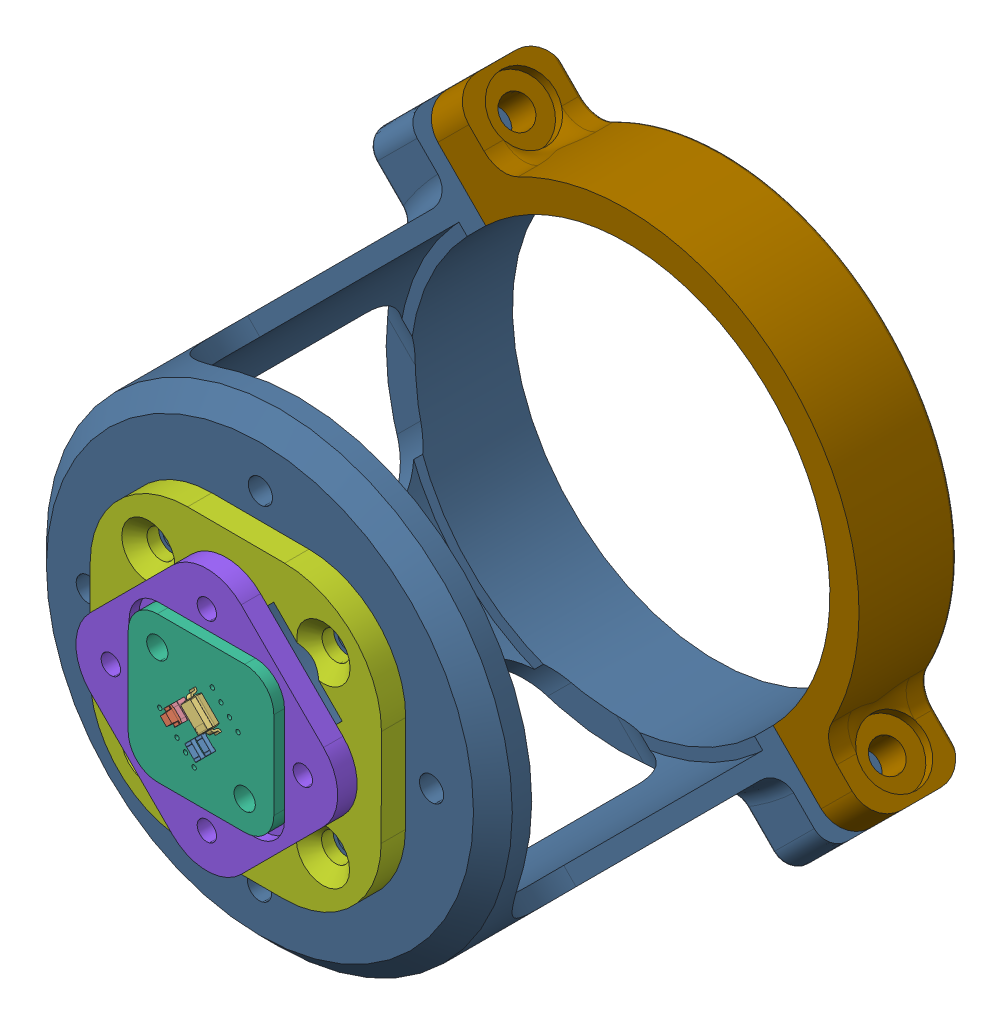
SolidWorks assembly NEW_AS5047_mount_ASS, configuration Default. Lengths in mm.
Overall size (78.46 78.52 54.41).
18 component instances, 10 part files, 13 mates.
Components (placement in the parent):
- as5047-mounting_v2.0.step-1: as5047-mounting_v2.0.step [Default] at (-37.8723 -4.0451 22.4905) size (15 15 3.95)
  - R_0603_1608Metric.step-1: R_0603_1608Metric.step [Default] at (4.1664 -6.9571 1.65) x (-0.707107 0.707107 0) z (0 0 1) size (1.6 0.8 0.45)
    - R_0603_1608Metric-0.step-1: R_0603_1608Metric-0.step [Default] at origin size (1.6 0.8 0.45)
  - LED_0603_1608Metric.step-1: LED_0603_1608Metric.step [Default] at (2.0554 -4.8494 1.65) x (0.707107 -0.707107 0) z (0 0 1) size (1.6 0.8 1.1)
    - LED_0603_1608Metric-1.step-1: LED_0603_1608Metric-1.step [Default] at origin size (1.6 0.8 1.1)
  - D_SOD-123.step-1: D_SOD-123.step [Default] at (5.1024 -3.0451 1.65) x (-0.707107 0.707107 0) z (0 0 1) size (3.8 1.6 1.25)
    - D_SOD_123.step-1: D_SOD_123.step [Default] at origin size (3.8 1.6 1.25)
  - C_0603_1608Metric.step-1: C_0603_1608Metric.step [Default] at (3.1284 -3.7888 1.65) x (-0.707107 0.707107 0) z (0 0 1) size (1.6 0.8 0.8)
    - C_0603_1608Metric-2.step-1: C_0603_1608Metric-2.step [Default] at origin size (1.6 0.8 0.8)
  - R_0603_1608Metric.step-2: R_0603_1608Metric.step [Default] at (5.2316 -5.892 1.65) x (-0.707107 0.707107 0) z (0 0 1) size (1.6 0.8 0.45)
    - R_0603_1608Metric-0.step-1: R_0603_1608Metric-0.step [Default] at origin size (1.6 0.8 0.45)
  - TSSOP-14_4.4x5mm_P0.65mm.step-1: TSSOP-14_4.4x5mm_P0.65mm.step [Default] at (4.5042 -4.549 -0.05) x (0.707107 -0.707107 0) z (0 0 -1) size (6.4 5 1)
    - TSSOP_14_44x5mm_P065mm.step-1: TSSOP_14_44x5mm_P065mm.step [Default] at origin size (6.4 5 1)
  - as5047-mounting_v2.0_PCB.step-1: as5047-mounting_v2.0_PCB.step [Default] at origin size (15 15 1.6)
- SENSOR_SUPP_PL^ROBO_MOTOR_M3508-1: SENSOR_SUPP_PL^ROBO_MOTOR_M3508 [Default] at (-33.4013 -8.5561 17.9905) x (0.999996 -0.002924 0) z (0 0 1) size (30 30 3.5)
- NEW_AS5047_mount-1: NEW_AS5047_mount [Default] at (-33.3723 -8.5451 23.4905) x (0.707107 -0.707107 0) z (0.707107 0.707107 0) size (22 2 22)
- CLAMP_HALF^ROBO_MOTOR_M3508-1: CLAMP_HALF^ROBO_MOTOR_M3508 [Default] at (-32.6921 -7.851 -56.5095) x (0.709172 0.705036 0) z (0.705036 -0.709172 0) size (23.5 10 62)
- SW_SENSOR_CL_RING^ROBO_MOTOR_M3508-1: SW_SENSOR_CL_RING^ROBO_MOTOR_M3508 [Default] at (-33.4013 -8.5561 -23.0095) x (0.709172 0.705036 0) z (0.705036 -0.709172 0) size (48 47.01 62)
Mates (geometry in assembly coordinates):
- Coincident3: coincident anti-aligned: plane of as5047-mounting_v2.0.step-1/as5047-mounting_v2.0_PCB.step-1 through (-33.3723 -8.5451 22.4905) normal (0 0 -1); plane of NEW_AS5047_mount-1 through (-33.3723 -8.5451 22.4905) normal (0 0 1)
- Concentric3: concentric anti-aligned: cylinder of SENSOR_SUPP_PL^ROBO_MOTOR_M3508-1 through (-33.3723 1.3434 17.9905) axis (0 0 -1) radius 0.7; cylinder of NEW_AS5047_mount-1 through (-33.3723 1.3434 21.4905) axis (0 0 1) radius 1
- Parallel3: parallel anti-aligned: plane of as5047-mounting_v2.0.step-1/as5047-mounting_v2.0_PCB.step-1 through (-28.8723 -16.0451 22.4905) normal (0 -1 0); plane of NEW_AS5047_mount-1 through (-33.3723 -16.5451 22.4905) normal (0 1 0)
- Parallel4: parallel anti-aligned: plane of as5047-mounting_v2.0.step-1/as5047-mounting_v2.0_PCB.step-1 through (-40.8723 -13.0451 22.4905) normal (-1 0 0); plane of NEW_AS5047_mount-1 through (-41.3723 -8.5451 22.4905) normal (1 0 0)
- Distance1: distance = 0.5 mm anti-aligned: plane of as5047-mounting_v2.0.step-1/as5047-mounting_v2.0_PCB.step-1 through (-28.8723 -16.0451 22.4905) normal (0 -1 0); plane of NEW_AS5047_mount-1 through (-33.3723 -16.5451 22.4905) normal (0 1 0)
- Distance2: distance = 0.5 mm anti-aligned: plane of as5047-mounting_v2.0.step-1/as5047-mounting_v2.0_PCB.step-1 through (-40.8723 -13.0451 22.4905) normal (-1 0 0); plane of NEW_AS5047_mount-1 through (-41.3723 -8.5451 22.4905) normal (1 0 0)
- Coincident7: coincident anti-aligned: plane of SENSOR_SUPP_PL^ROBO_MOTOR_M3508-1 through (-31.4303 -18.4614 21.4905) normal (0 0 1); plane of NEW_AS5047_mount-1 through (-33.3723 -8.5451 21.4905) normal (0 0 -1)
- Concentric11: concentric aligned: cylinder of SENSOR_SUPP_PL^ROBO_MOTOR_M3508-1 through (-24.4121 -17.598 20.4905) axis (0 0 1) radius 1.45; cylinder of SW_SENSOR_CL_RING^ROBO_MOTOR_M3508-1 through (-24.4121 -17.598 17.9905) axis (0 0 1) radius 1.025
- Concentric12: concentric aligned: cylinder of SENSOR_SUPP_PL^ROBO_MOTOR_M3508-1 through (-42.3905 0.4859 20.4905) axis (0 0 1) radius 1.45; cylinder of SW_SENSOR_CL_RING^ROBO_MOTOR_M3508-1 through (-42.3905 0.4859 17.9905) axis (0 0 1) radius 1.025
- Coincident8: coincident anti-aligned: plane of SENSOR_SUPP_PL^ROBO_MOTOR_M3508-1 through (-33.4013 -8.5561 17.9905) normal (0 0 -1); plane of SW_SENSOR_CL_RING^ROBO_MOTOR_M3508-1 through (-49.0031 -24.0668 17.9905) normal (0 0 1)
- Concentric13: concentric anti-aligned: cylinder of CLAMP_HALF^ROBO_MOTOR_M3508-1 through (-10.074 -23.51 -24.0095) axis (0.709172 0.705036 0) radius 1.6; cylinder of SW_SENSOR_CL_RING^ROBO_MOTOR_M3508-1 through (2.6911 -10.8194 -24.0095) axis (-0.709172 -0.705036 0) radius 1.7
- Concentric14: concentric anti-aligned: cylinder of CLAMP_HALF^ROBO_MOTOR_M3508-1 through (-48.2186 14.8583 -24.0095) axis (0.709172 0.705036 0) radius 1.6; cylinder of SW_SENSOR_CL_RING^ROBO_MOTOR_M3508-1 through (-35.4535 27.549 -24.0095) axis (-0.709172 -0.705036 0) radius 1.7
- Distance3: distance = 2 mm anti-aligned: plane of SW_SENSOR_CL_RING^ROBO_MOTOR_M3508-1 through (-50.6767 8.1115 -29.0095) normal (0.709172 0.705036 0); plane of CLAMP_HALF^ROBO_MOTOR_M3508-1 through (-32.3375 -7.4985 -56.5095) normal (-0.709172 -0.705036 0)
